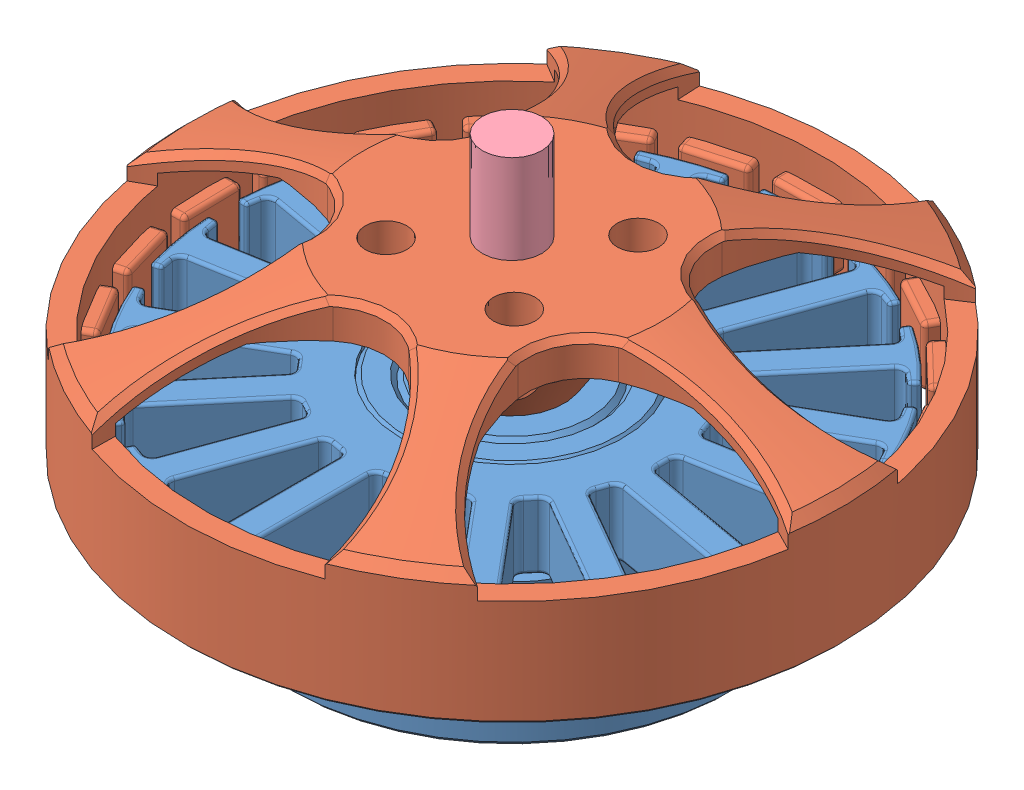
SolidWorks assembly motor_antigravity_4004, configuration Standard. Lengths in mm.
Overall size (45.19 27.5 45.19).
4 component instances, 4 part files, 6 mates.
Components (placement in the parent):
- motor_antigravity_4004_stator-1: motor_antigravity_4004_stator [Standard] at origin size (38.93 11.2 39)
- motor_antigravity_4004_rotor-1: motor_antigravity_4004_rotor [Standard] at (0 19.2 0) x (0.99984 0 -0.017865) z (0.017865 0 0.99984) size (44.4 12.8 44.4)
- motor_antigravity_4004_brass_spacer-1: motor_antigravity_4004_brass_spacer [Standard] at (0 -0.86 0) x (-0.554726 0 0.832033) z (-0.832033 0 -0.554726) size (5.5 0.86 5.5)
- motor_antigravity_4004_shaft-1: motor_antigravity_4004_shaft [Default] at (0 -2.3 0) x (0.999997 0 -0.002312) z (0 1 0) size (4 4 27.5)
Mates (geometry in assembly coordinates):
- Deckungsgleich1: coincident aligned: line of motor_antigravity_4004_stator-1 through (12.32 0 -0.56) axis (0 0 1); line of motor_antigravity_4004_rotor-1 through (30.03 0 -3.715) axis (0 0 1)
- Deckungsgleich2: coincident anti-aligned: plane of motor_antigravity_4004_stator-1 through (0 11.2 0) normal (0 1 0); plane of motor_antigravity_4004_rotor-1 through (-0.0625 11.2 -3.4994) normal (0 -1 0)
- Deckungsgleich10: coincident anti-aligned: plane of motor_antigravity_4004_stator-1 through (0 0 0) normal (0 -1 0); plane of motor_antigravity_4004_brass_spacer-1 through (0 0 0) normal (0 1 0)
- Concentric1: concentric anti-aligned: cylinder of motor_antigravity_4004_rotor-1 through (0 53.4712 0) axis (0 1 0) radius 2; cylinder of motor_antigravity_4004_shaft-1 through (0 25.2 0) axis (0 -1 0) radius 2
- Distance1: distance = 6 mm aligned: plane of motor_antigravity_4004_shaft-1 through (0 25.2 0) normal (0 1 0); plane of motor_antigravity_4004_rotor-1 through (-0.0357 19.2 -1.9997) normal (0 1 0)
- Concentric2: concentric aligned: cylinder of motor_antigravity_4004_brass_spacer-1 through (0 0 0) axis (0 -1 0) radius 2; cylinder of motor_antigravity_4004_shaft-1 through (0 25.2 0) axis (0 -1 0) radius 2
